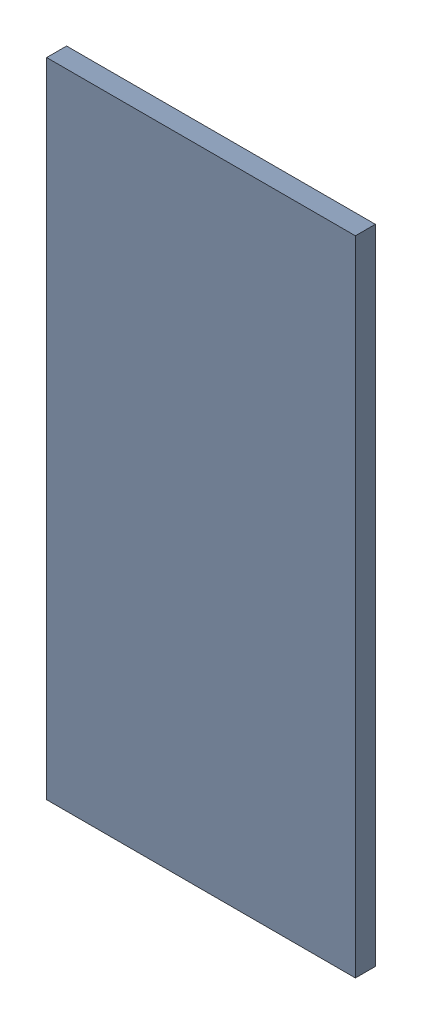
SolidWorks assembly Pad ADXL345-8(19mm,55.903mm) on Top Layer, configuration Predeterminado. Lengths in mm.
Overall size (0.55 1.15 0.04).
2 component instances, 1 part files, 0 mates.
Components (placement in the parent):
- Pad ADXL345-8(19mm,55.903mm) on Top Layer-1-1: Pad ADXL345-8(19mm,55.903mm) on Top Layer-1 [Predeterminado] at (-68.317 -44.187 -0.0457) size (0.55 1.15 0.04)
  - Pad ADXL345-8(19mm,55.903mm) on Top Layer-Part-1-1: Pad ADXL345-8(19mm,55.903mm) on Top Layer-Part-1 [Predeterminado] at origin size (0.55 1.15 0.04)
